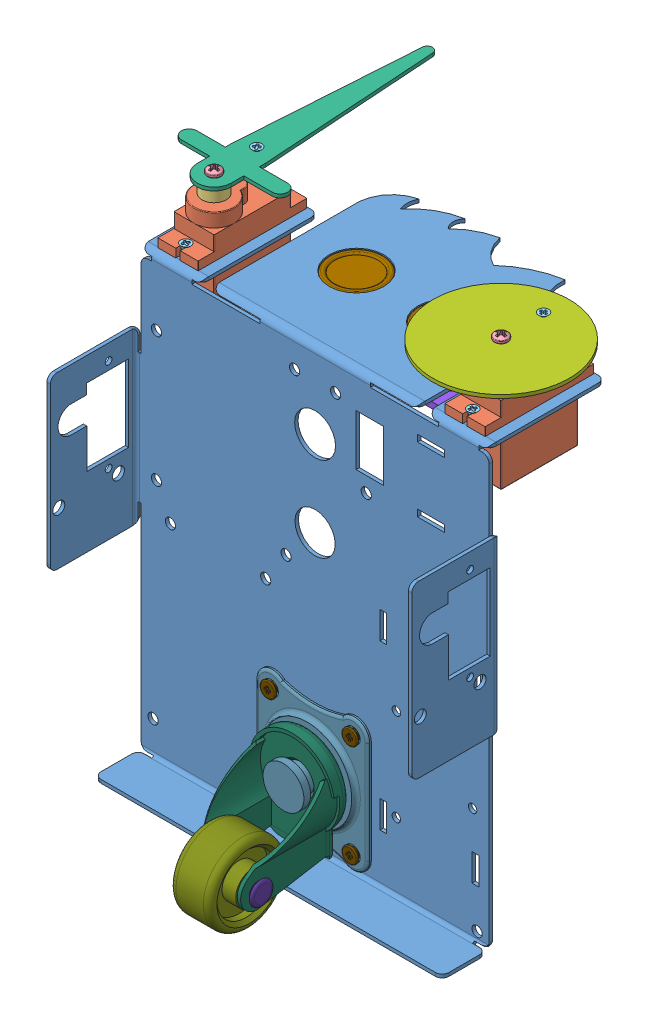
SolidWorks assembly MS_AC, configuration Predeterminado. Lengths in mm.
Overall size (151 194.25 114.03).
41 component instances, 18 part files, 10 mates.
Components (placement in the parent):
- DYOR_MetalSheet_Accessory-1: DYOR_MetalSheet_Accessory [Predeterminado] at (87.5156 -142.111 138.6754) size (151 194.25 79.67)
- AC-1: AC [Predeterminado] at (1.4737 -13.8185 -2.1465) size (119.83 34.06 84.1)
  - sg90-1: sg90 [Default] at (182.9409 -195.7135 134.2781) x (0 0 -1) z (1 0 0) size (31.9 29.9 11.8)
  - sg90-2: sg90 [Default] at (98.7972 -195.7135 134.2781) x (0 0 -1) z (1 0 0) size (31.9 29.9 11.8)
  - SG90 plastic Horn-1: SG90 plastic Horn [Default] at (188.8409 -166.2635 128.3781) x (-0.029359 0 -0.999569) z (0.999569 0 -0.029359) size (19.4 4 7.07)
  - SG90 plastic Horn-2: SG90 plastic Horn [Default] at (104.6972 -166.2635 128.3781) x (-0.012387 0 -0.999923) z (0.999923 0 -0.012387) size (19.4 4 7.07)
  - (M2_3_mm)_90116A007_METRIC 316 SS PAN HEAD PHILLIPS MACHINE SCREW-1: (M2_3_mm)_90116A007_METRIC 316 SS PAN HEAD PHILLIPS MACHINE SCREW [90116A007] at (104.6972 -166.2635 128.3781) x (-1 0 0) z (0 1 0) size (4 4 4.68)
  - (M2_3_mm)_90116A007_METRIC 316 SS PAN HEAD PHILLIPS MACHINE SCREW-2: (M2_3_mm)_90116A007_METRIC 316 SS PAN HEAD PHILLIPS MACHINE SCREW [90116A007] at (188.8409 -166.2635 128.3781) x (-1 0 0) z (0 1 0) size (4 4 4.68)
  - M2x6 SelfTap Screw-1: M2x6 SelfTap Screw [Predeterminado] at (104.6972 -162.7635 115.8781) x (0.825172 0 -0.564882) z (0 1 0) size (3.4 3.28 6)
  - M2x6 SelfTap Screw-2: M2x6 SelfTap Screw [Predeterminado] at (188.7787 -162.7635 115.8783) x (0.001298 0 -0.999999) z (0 1 0) size (3.4 3.28 6)
  - M2x6 SelfTap Screw-3: M2x6 SelfTap Screw [Predeterminado] at (104.6972 -176.8135 109.3781) x (-0.923728 0 -0.383049) z (0 1 0) size (3.4 3.28 6)
  - M2x6 SelfTap Screw-4: M2x6 SelfTap Screw [Predeterminado] at (104.6972 -176.8135 136.6781) x (-0.923728 0 -0.383049) z (0 1 0) size (3.4 3.28 6)
  - M2x6 SelfTap Screw-5: M2x6 SelfTap Screw [Predeterminado] at (188.8409 -176.8135 136.6781) x (0.923728 0 0.383049) z (0 1 0) size (3.4 3.28 6)
  - M2x6 SelfTap Screw-6: M2x6 SelfTap Screw [Predeterminado] at (188.8409 -176.8135 109.3781) x (0.923728 0 0.383049) z (0 1 0) size (3.4 3.28 6)
  - Sword-1: Sword [Predeterminado] at (59.4912 -163.2635 112.6165) x (1 0 0) z (0 1 0) size (31.17 69 1)
  - Shield-1: Shield [Predeterminado] at (233.9679 -164.2635 112.3919) x (-0.999988 0 0.004973) z (0 -1 0) size (40 40 1)
- HC-SR04 Ping Sensor-1: HC-SR04 Ping Sensor [Default] at (148.2146 -207.382 113.5316) x (0 0 -1) z (0 1 0) size (25.18 45 18.07)
  - PCB-1: PCB [Default] at origin size (20.5 45 1.75)
  - Transducer-1: Transducer [Default] at (0 -13 13.25) x (1 0 0) z (0 -1 0) size (15.88 12 15.88)
  - Transducer-2: Transducer [Default] at (0 13 13.25) x (1 0 0) z (0 -1 0) size (15.88 12 15.88)
  - 3 Pin Header 90 Degree-1: 3 Pin Header 90 Degree [Default] at (8.4275 0 -1.25) x (-1 0 0) z (0 -1 0) size (8 7.82 10)
  - 14 Pin SMT-1: 14 Pin SMT [Default] at (-0.35 -18.5 -0.85) x (0 -1 0) z (1 0 0) size (6 1.6 8.8)
  - 14 Pin SMT-2: 14 Pin SMT [Default] at (0 -0.3826 -0.85) x (1 0 0) z (0 1 0) size (6 1.6 8.8)
  - 14 Pin SMT-3: 14 Pin SMT [Default] at (0 17.5274 -0.85) x (1 0 0) z (0 1 0) size (6 1.6 8.8)
  - Cap1 SMT-1: Cap1 SMT [Default] at (-1.755 7.4774 -0.9689) x (0 1 0) z (-1 0 0) size (4.5 1.84 1.75)
  - Cap1 SMT-2: Cap1 SMT [Default] at (6.835 7.4774 -0.9689) x (0 1 0) z (-1 0 0) size (4.5 1.84 1.75)
  - Cap1 SMT-3: Cap1 SMT [Default] at (-6.835 7.4774 -0.9689) x (0 1 0) z (-1 0 0) size (4.5 1.84 1.75)
  - Cap1 SMT-4: Cap1 SMT [Default] at (4.295 7.4774 -0.9689) x (0 1 0) z (-1 0 0) size (4.5 1.84 1.75)
  - Cap1 SMT-5: Cap1 SMT [Default] at (1.755 7.4774 -0.9689) x (0 1 0) z (-1 0 0) size (4.5 1.84 1.75)
  - Cap1 SMT-6: Cap1 SMT [Default] at (-4.295 7.4774 -0.9689) x (0 1 0) z (-1 0 0) size (4.5 1.84 1.75)
  - HC-SR04 Crystal-1: HC-SR04 Crystal [Default] at (-8.3 0 1.75) x (0 -1 0) z (0 0 1) size (10 3.5 2.7)
- CA-1: CA [Predeterminado] at (0 -1.6781 0) size (33 45.94 42.59)
  - Caster Wheel-1: Caster Wheel [Default] at (194.2283 -297.83 183.8938) x (0 1 0) z (-1 0 0) size (45.94 37.59 33)
    - caster holder-1: caster holder [Default] at (-24.0751 44.7184 29.5137) x (1 0 0) z (0 0 -1) size (39 9.27 33)
    - holder-1: holder [Default] at (-1.5751 42.9484 46.0137) x (0 0 1) z (1 0 0) size (25 28.07 31.31)
    - caster wheel-1: caster wheel [Default] at (-15.6961 19.9484 46.0137) x (0.997275 0.073773 0) z (0 0 1) size (23 23 14)
    - Part4-1: Part4 [Default] at (-15.6961 19.9484 55.0137) x (-0.978448 0.206495 0) z (0 0 -1) size (7 7 20)
  - M3x6 SelfTap Screw-1: M3x6 SelfTap Screw [Predeterminado] at (136.2146 -284.4051 140.6754) size (4.62 4.62 7)
  - M3x6 SelfTap Screw-2: M3x6 SelfTap Screw [Predeterminado] at (136.2146 -314.4051 140.6754) size (4.62 4.62 7)
  - M3x6 SelfTap Screw-3: M3x6 SelfTap Screw [Predeterminado] at (160.2146 -284.4051 140.6754) size (4.62 4.62 7)
  - M3x6 SelfTap Screw-4: M3x6 SelfTap Screw [Predeterminado] at (160.2146 -314.4051 140.6754) size (4.62 4.62 7)
Mates (geometry in assembly coordinates):
- Coincidente421: coincident: plane of DYOR_MetalSheet_Accessory-1 through (99.2146 -193.632 136.5875) normal (0 1 0); plane of AC-1/sg90-1 through (196.2146 -193.632 104.9316) normal (0 -1 0)
- Concéntrica264: concentric: circle of DYOR_MetalSheet_Accessory-1; circle of HC-SR04 Ping Sensor-1/Transducer-1
- Paralelo86: parallel: plane of DYOR_MetalSheet_Accessory-1 through (99.2146 -193.1879 137.6754) normal (0 0 -1); plane of HC-SR04 Ping Sensor-1/PCB-1 through (125.7146 -205.632 123.7816) normal (0 0 1)
- Coincidente423: coincident: plane of DYOR_MetalSheet_Accessory-1 through (99.2146 -193.632 136.5875) normal (0 1 0); plane of HC-SR04 Ping Sensor-1/Transducer-1 through (161.2146 -193.632 105.5916) normal (0 1 0)
- Concéntrica293: concentric: circle of DYOR_MetalSheet_Accessory-1; circle of ?
- Concéntrica294: concentric: circle of DYOR_MetalSheet_Accessory-1; circle of ?
- Coincidente490: coincident: plane of DYOR_MetalSheet_Accessory-1 through (99.2146 -193.1879 138.6754) normal (0 0 1); plane of CA-1/Caster Wheel-1/caster holder-1 through (148.2146 -256.285 138.6754) normal (0 0 -1)
- Concéntrica295: concentric: circle of DYOR_MetalSheet_Accessory-1; circle of CA-1/Caster Wheel-1/caster holder-1
- Concéntrica296: concentric: circle of DYOR_MetalSheet_Accessory-1; circle of AC-1/M2x6 SelfTap Screw-6
- Concéntrica297: concentric: circle of DYOR_MetalSheet_Accessory-1; circle of AC-1/M2x6 SelfTap Screw-5
